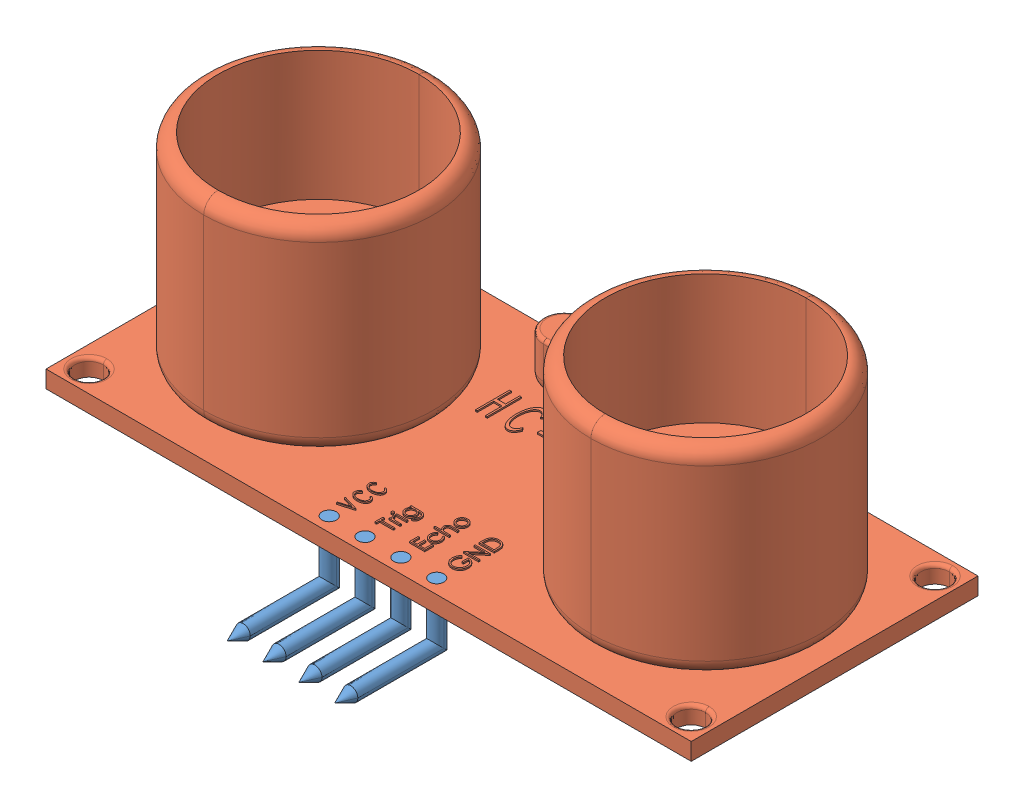
SolidWorks assembly Assem3, configuration Default. Lengths in mm.
Overall size (45 18.3 26.12).
8 component instances, 3 part files, 0 mates.
Components (placement in the parent):
- Assem3.STEP-1: Assem3.STEP [Default] at origin size (45 18.3 26.12)
  - pin header.STEP-1: pin header.STEP [Default] at (-4.1109 -10.7267 50.9724) x (0 0 -1) z (1 0 0) size (7.62 4.5 1)
  - UltraSonic.STEP-1: UltraSonic.STEP [Default] at (-2.8609 -7.9267 1.7996) size (45 15 20)
  - pin header.STEP-2: pin header.STEP [Default] at (0.8891 -10.7267 50.9724) x (0 0 -1) z (1 0 0) size (7.62 4.5 1)
  - part2.STEP-1: part2.STEP [Default] at (-16.3609 -2.9267 1.7996) x (0.862539 0 -0.505991) z (0.505991 0 0.862539) size (8 0.63 8)
  - pin header.STEP-3: pin header.STEP [Default] at (-6.6109 -10.7267 50.9724) x (0 0 -1) z (1 0 0) size (7.62 4.5 1)
  - pin header.STEP-4: pin header.STEP [Default] at (-1.6109 -10.7267 50.9724) x (0 0 -1) z (1 0 0) size (7.62 4.5 1)
  - part2.STEP-2: part2.STEP [Default] at (10.6391 -2.6926 1.7996) x (0.988186 0 -0.153259) z (0.153259 0 0.988186) size (8 0.63 8)
